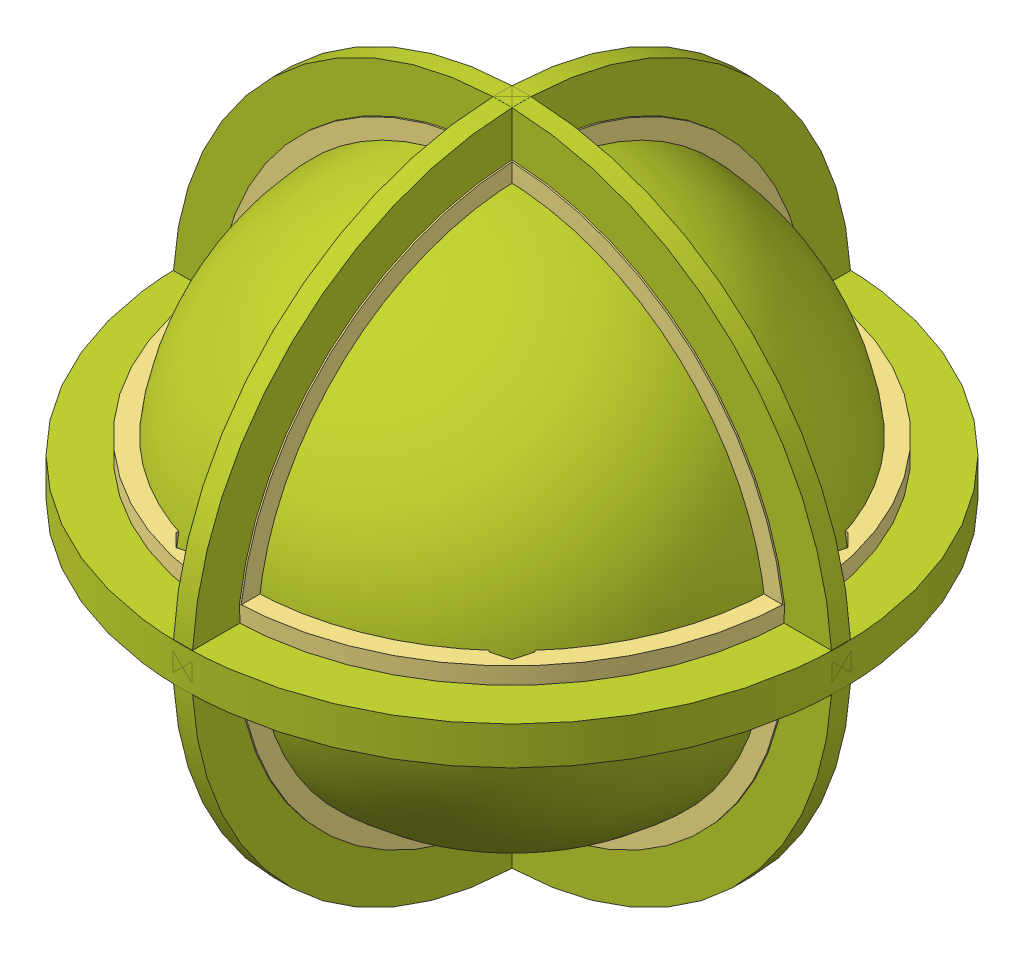
SolidWorks assembly Drifter2_Assem_GSM, configuration Default. Lengths in mm.
Overall size (104 104 104).
11 component instances, 7 part files, 19 mates.
Components (placement in the parent):
- Sparkfun_NEO-M8P-1: Sparkfun_NEO-M8P [Default] at (27.8484 1.5059 0) x (0 -1 0) z (0 0 1) size (33 4.73 41.24)
- Teensy_3-2-1: Teensy_3-2 [Default] at (19.9056 7.9504 0) x (0 0 -1) z (0 -1 0) size (35.56 4.07 17.78)
- Housing2_Boss-1: Housing2_Boss [2-230 O-ring] at origin size (89 44.86 89) (hidden)
- Housing2_Boss-2: Housing2_Boss [Housing TOP] x (1 0 0) z (0 0 -1) size (89 48.86 89) (hidden)
- EXVIST_4GLTEGSM_EC25-AFX-1: EXVIST_4GLTEGSM_EC25-AFX [USB_desolder] at (-19.7642 4.7661 -22.5005) x (0 0 1) z (0 -1 0) size (49.74 7.08 29.97)
- Battery_AllSizes_configurations-5: Battery_AllSizes_configurations [500mAH] at (0 24.475 -9.8263) x (1 0 0) z (0 1 0) size (31 9 20)
- Battery_AllSizes_configurations-6: Battery_AllSizes_configurations [500mAH] at (0 24.475 9.8263) x (1 0 0) z (0 -1 0) size (31 9 20)
- Battery_AllSizes_configurations-7: Battery_AllSizes_configurations [500mAH] at (0 27.6651 0) x (1 0 0) z (0 1 0) size (31 9 20)
- MA104.C.AB.015_AXIS-1: MA104.C.AB.015_AXIS [Default] at (0 -10.6356 0) x (1 0 0) z (0 -1 0) size (48.81 49.43 49.77)
  - MA104.C.AB.015-1: MA104.C.AB.015 [Default] at (10.5424 -0.5484 -13.2956) size (48.81 49.43 51.31)
- BALL-1: BALL [80mm] at origin size (104 104 104)
Mates (geometry in assembly coordinates):
- Parallel1: parallel aligned: plane of Teensy_3-2-1 through (21.4756 16.8404 17.78) normal (0 0 1)
- Parallel5: parallel anti-aligned: plane of Sparkfun_NEO-M8P-1 through (29.4384 18.0059 -20.62) normal (0 0 -1)
- Angle5: planar angle = 1.570796 rad aligned: plane of Teensy_3-2-1 through (21.4756 -0.9396 17.78) normal (0 -1 0)
- Angle4: planar angle = 1.570796 rad aligned: plane of Sparkfun_NEO-M8P-1 through (29.4384 -14.9941 20.62) normal (0 -1 0)
- Coincident17: coordinate: point of Housing2_Boss-1
- Angle6: planar angle = 1.570796 rad aligned: plane of EXVIST_4GLTEGSM_EC25-AFX-1 through (-19.7642 4.7661 -22.5005) normal (0 -1 0)
- Coincident26: coincident aligned: plane of Battery_AllSizes_configurations-5 through (0 24.475 -9.8263) normal (1 0 0)
- Angle3: planar angle = 1.570796 rad aligned: plane of Battery_AllSizes_configurations-5 through (0 24.475 -9.8263) normal (0 1 0)
- Coincident28: coincident: unknown of Battery_AllSizes_configurations-7
- Coincident29: coincident anti-aligned: plane of Battery_AllSizes_configurations-7 through (0 27.6651 0) normal (0 0 -1)
- Coincident32: coincident aligned: plane of Battery_AllSizes_configurations-7 through (0 27.6651 0) normal (1 0 0)
- Coincident35: coincident: unknown of MA104.C.AB.015_AXIS-1
- Parallel12: parallel anti-aligned: plane of MA104.C.AB.015_AXIS-1 through (0 -10.6356 0) normal (0 -1 0)
- Coincident38: coincident aligned: plane of MA104.C.AB.015_AXIS-1 through (0 -10.6356 0) normal (0 0 1)
- Coincident39: coordinate: unknown of BALL-1
- Coincident40: coincident: unknown of BALL-1
- Coincident41: coincident: unknown of Sparkfun_NEO-M8P-1
- Coincident42: coincident: unknown of Teensy_3-2-1
- Coincident44: coincident anti-aligned: plane of EXVIST_4GLTEGSM_EC25-AFX-1 through (-19.7642 4.7661 0) normal (0 0 -1)
